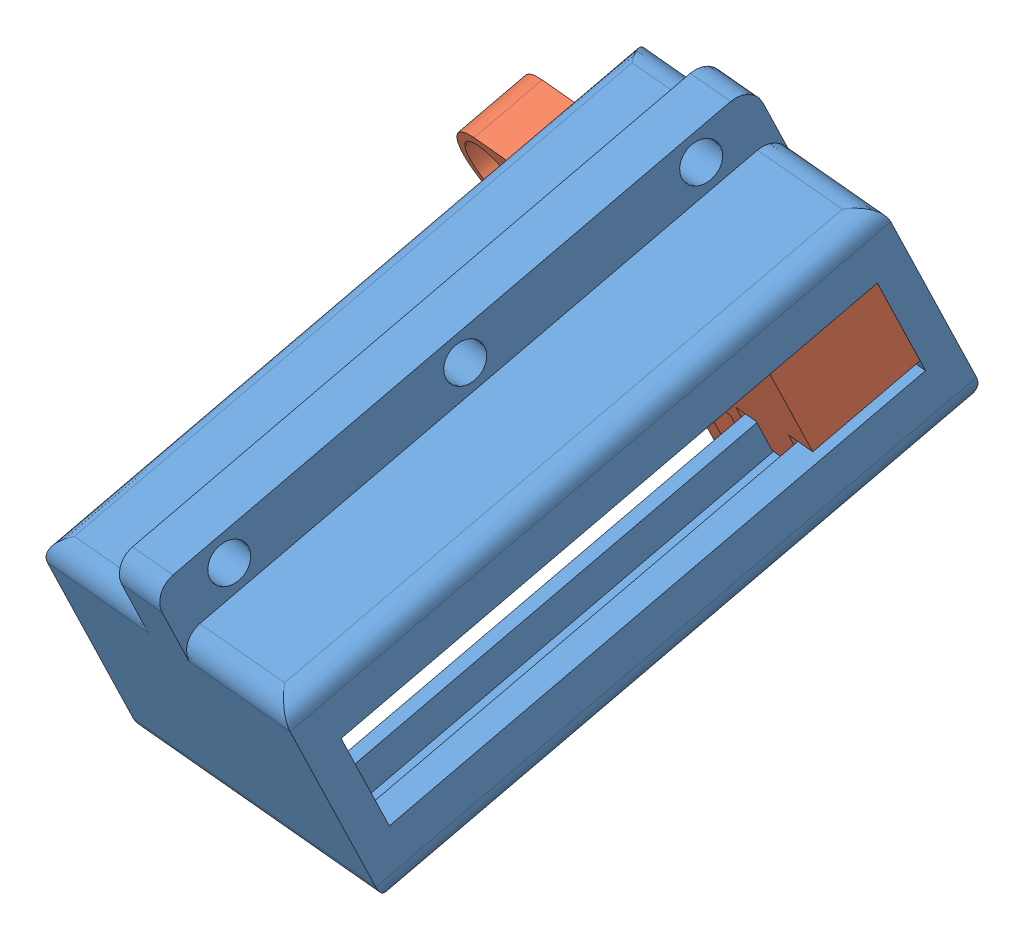
SolidWorks assembly transmission_assem, configuration Default. Lengths in mm.
Overall size (23.67 23.7 33.62).
2 component instances, 2 part files, 5 mates.
Components (placement in the parent):
- transmissionblockdraft1-1: transmissionblockdraft1 [Default] at (-40.5711 36.7905 123.7047) x (0.976963 0.104487 0.18608) z (-0.13362 -0.380383 0.915125) size (15 12.5 28)
- transmission_slider-2: transmission_slider [Default] at (-32.9725 47.1445 105.6239) x (0.976963 0.104487 0.18608) z (-0.13362 -0.380383 0.915125) size (21.5 12 5)
Mates (geometry in assembly coordinates):
- Parallel20: parallel anti-aligned: plane of transmissionblockdraft1-1 through (-33.4495 56.8788 83.0956) normal (0.976963 0.104487 0.18608); plane of transmission_slider-2 through (-35.6269 50.0651 100.9866) normal (-0.976963 -0.104487 -0.18608)
- Parallel21: parallel aligned: plane of transmissionblockdraft1-1 through (-36.8298 47.4413 98.0812) normal (0.13362 0.380383 -0.915125); plane of transmission_slider-2 through (-32.3044 49.0464 101.0483) normal (0.13362 0.380383 -0.915125)
- Coincident7: coincident anti-aligned: plane of transmissionblockdraft1-1 through (-25.5304 62.6435 86.648) normal (0.166401 -0.918908 -0.357659); plane of transmission_slider-2 through (-27.6246 55.3703 104.3602) normal (-0.166401 0.918908 0.357659)
- Distance2: distance = 0.01 mm anti-aligned: plane of transmission_slider-2 through (-27.9306 50.1857 102.1605) normal (0.976963 0.104487 0.18608); plane of transmissionblockdraft1-1 through (-24.9319 55.2138 83.6472) normal (-0.976963 -0.104487 -0.18608)
- LimitDistance5: limit distance = 0 mm anti-aligned: plane of transmission_slider-2 through (-32.3044 49.0464 101.0483) normal (0.13362 0.380383 -0.915125); plane of transmissionblockdraft1-1 through (-37.0302 46.8707 99.4539) normal (-0.13362 -0.380383 0.915125)
